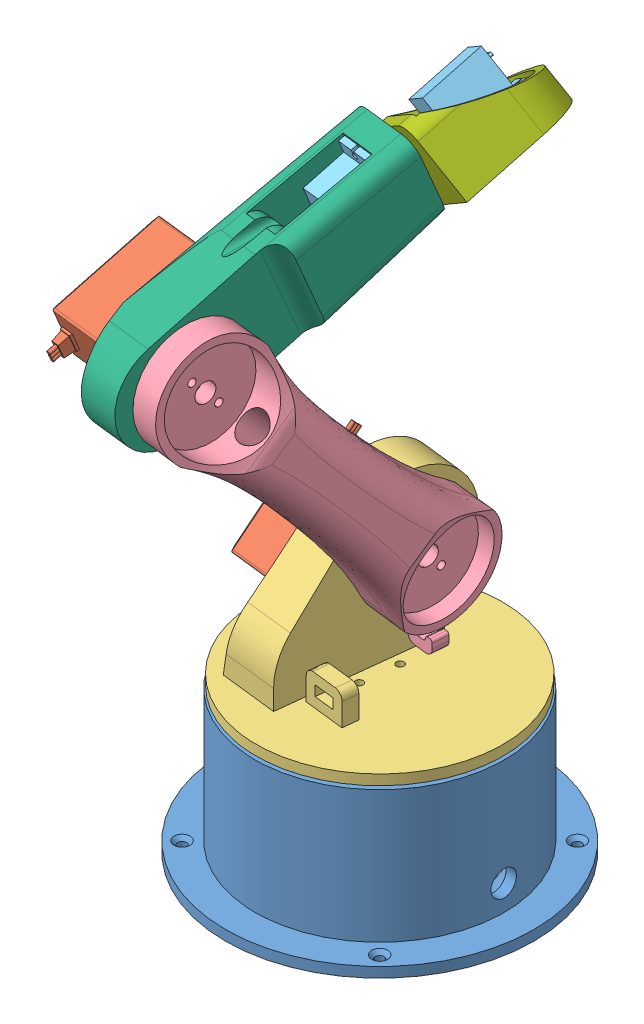
SolidWorks assembly Robotic Arm, configuration Default. Lengths in mm.
Overall size (121.25 257.34 174.58).
10 component instances, 7 part files, 24 mates.
Components (placement in the parent):
- Base-1: Base [Default] at (40.7793 36.1076 92.8796) size (121.25 56 121.25)
- Servo Motor MG996R-1: Servo Motor MG996R [Default] at (30.5293 45.3076 92.8796) x (-1 0 0) z (0 0 -1) size (55.8 47.4 21)
- Waist-1: Waist [Default] at (40.7793 93.1076 92.8796) x (0.993555 0 0.113355) z (-0.113355 0 0.993555) size (97 64.78 97)
- Servo Motor MG996R-2: Servo Motor MG996R [Default] at (-7.3675 126.313 80.8505) x (-0.080154 -0.707107 0.702549) z (-0.080154 0.707107 0.702549) size (55.8 47.4 21)
- Arm 01-1: Arm 01 [Default] at (40.5486 133.5608 79.0224) x (0.085272 0.658869 -0.747409) z (0.993555 0 0.113355) size (54.87 166.68 26.36)
- Servo Motor Micro  9g-1: Servo Motor Micro  9g [Default] at (27.4329 247.0974 99.587) x (-0.042658 0.926487 0.3739) z (-0.993555 0 -0.113355) size (32.6 29.9 12.4)
- Servo Motor MG996R-7: Servo Motor MG996R [Default] at (-14.4318 227.6891 142.7687) x (0.105022 0.376326 -0.920516) z (0.042658 -0.926487 -0.3739) size (55.8 47.4 21)
- Arm 02 v3-1: Arm 02 v3 [Default] at (30.0586 237.1407 125.0931) x (-0.042658 0.926487 0.3739) z (-0.993555 0 -0.113355) size (38.57 115 28.32)
- Arm 03-1: Arm 03 [Default] at (34.5638 256.4879 71.7578) x (0.75464 0.572691 0.320225) z (-0.64768 0.728289 0.223845) size (33 46 28)
- Servo Motor Micro  9g-2: Servo Motor Micro  9g [Default] at (27.5451 275.7024 53.9349) x (-0.105022 -0.376326 0.920516) z (0.75464 0.572691 0.320225) size (32.6 29.9 12.4)
Mates (geometry in assembly coordinates):
- Coincident1: coincident: plane of Base-1 through (40.7793 74.1076 105.8796) normal (0 1 0); plane of Servo Motor MG996R-1 through (57.8293 74.1076 102.1296) normal (0 -1 0)
- Concentric1: concentric: cylinder of Base-1 through (54.5293 66.9076 87.8796) axis (0 1 0) radius 1.3; cylinder of Servo Motor MG996R-1 through (54.5293 69.7076 87.8796) axis (0 1 0) radius 2.1
- Concentric4: concentric: cylinder of Base-1 through (6.5293 66.9076 97.8796) axis (0 1 0) radius 1.3; cylinder of Servo Motor MG996R-1 through (6.5293 69.7076 97.8796) axis (0 1 0) radius 2.1
- Concentric5: concentric: cylinder of Base-1 through (40.7793 92.1076 92.8796) axis (0 -1 0) radius 49; cylinder of Waist-1 through (40.7793 97.1076 92.8796) axis (0 -1 0) radius 48.5
- Distance1: distance = 1 mm: plane of Base-1 through (40.7793 92.1076 92.8796) normal (0 1 0); plane of Waist-1 through (40.7793 93.1076 92.8796) normal (0 -1 0)
- Coincident4: coincident: plane of Waist-1 through (22.8953 93.1076 90.8392) normal (-0.993555 0 -0.113355); plane of Servo Motor MG996R-2 through (26.561 139.0763 58.709) normal (0.993555 0 0.113355)
- Coincident5: coincident: plane of Waist-1 through (-9.1378 119.0651 102.5331) normal (0.080154 0.707107 -0.702549); plane of Servo Motor MG996R-2 through (26.9293 119.0651 106.648) normal (-0.080154 -0.707107 0.702549)
- Coincident6: coincident: plane of Waist-1 through (-9.1378 119.0651 102.5331) normal (0.080154 -0.707107 -0.702549); plane of Servo Motor MG996R-2 through (30.2156 148.0565 77.8435) normal (-0.080154 0.707107 0.702549)
- Coincident7: coincident: plane of Servo Motor MG996R-2 through (40.5486 133.5608 79.0224) normal (0.993555 0 0.113355); plane of Arm 01-1 through (40.5486 133.5608 79.0224) normal (-0.993555 0 -0.113355)
- Concentric8: concentric: cylinder of Servo Motor MG996R-2 through (40.5486 133.5608 79.0224) axis (-0.993555 0 -0.113355) radius 10.5; cylinder of Arm 01-1 through (45.5163 133.5608 79.5891) axis (-0.993555 0 -0.113355) radius 21
- Coincident25: coincident: plane of Servo Motor MG996R-7 through (19.0396 246.5328 124.6339) normal (0.993555 0 0.113355); plane of Arm 02 v3-1 through (19.1295 237.1407 123.8462) normal (-0.993555 0 -0.113355)
- Coincident26: coincident: plane of Servo Motor MG996R-7 through (20.614 210.478 162.0009) normal (0.042658 -0.926487 -0.3739); plane of Arm 02 v3-1 through (14.8514 210.478 161.3435) normal (-0.042658 0.926487 0.3739)
- Coincident27: coincident: plane of Servo Motor MG996R-7 through (24.9199 225.9073 124.2598) normal (0.105022 0.376326 -0.920516); plane of Arm 02 v3-1 through (19.1573 225.9073 123.6023) normal (-0.105022 -0.376326 0.920516)
- Concentric13: concentric: cylinder of Arm 01-1 through (31.5852 223.8318 157.5769) axis (0.993555 0 0.113355) radius 3.75; cylinder of Servo Motor MG996R-7 through (31.5862 223.8318 157.577) axis (-0.993555 0 -0.113355) radius 10.5
- Coincident28: coincident: plane of Arm 01-1 through (40.5486 133.5608 79.0224) normal (-0.993555 0 -0.113355); plane of Servo Motor MG996R-7 through (31.5862 223.8318 157.577) normal (0.993555 0 0.113355)
- Concentric14: concentric: cylinder of Servo Motor Micro  9g-1 through (30.7906 253.6245 70.1567) axis (-0.105022 -0.376326 0.920516) radius 2.5; cylinder of Arm 02 v3-1 through (30.3863 252.1756 73.7006) axis (0.105022 0.376326 -0.920516) radius 6.5
- Coincident30: coincident: plane of Servo Motor Micro  9g-1 through (22.4732 268.9919 88.3634) normal (0.105022 0.376326 -0.920516); plane of Arm 02 v3-1 through (23.6724 236.4721 75.2055) normal (-0.105022 -0.376326 0.920516)
- Parallel3: parallel: plane of Servo Motor Micro  9g-1 through (36.417 245.0202 75.5372) normal (0.993555 0 0.113355); plane of Arm 02 v3-1 through (36.5886 236.4721 76.6791) normal (-0.993555 0 -0.113355)
- Concentric15: concentric: cylinder of Servo Motor Micro  9g-1 through (30.7906 253.6245 70.1567) axis (-0.105022 -0.376326 0.920516) radius 2.5; cylinder of Arm 03-1 through (32.0584 258.1671 59.0451) axis (-0.105022 -0.376326 0.920516) radius 2.5
- Coincident31: coincident: plane of Servo Motor Micro  9g-1 through (30.7906 253.6245 70.1567) normal (0.105022 0.376326 -0.920516); plane of Arm 03-1 through (34.5638 256.4879 71.7578) normal (-0.105022 -0.376326 0.920516)
- Concentric16: concentric: cylinder of Arm 03-1 through (46.572 256.829 42.8495) axis (-0.64768 0.728289 0.223845) radius 6.5; cylinder of Servo Motor Micro  9g-2 through (47.4463 255.8458 42.5473) axis (-0.64768 0.728289 0.223845) radius 2.5
- Parallel6: parallel: plane of Arm 03-1 through (38.9624 247.9896 56.2923) normal (0.75464 0.572691 0.320225); plane of Servo Motor Micro  9g-2 through (38.4963 260.1634 36.556) normal (-0.75464 -0.572691 -0.320225)
- Parallel9: parallel: plane of Arm 03-1 through (41.3779 256.6451 35.1205) normal (-0.105022 -0.376326 0.920516); plane of Servo Motor Micro  9g-2 through (47.8539 267.2647 40.5267) normal (0.105022 0.376326 -0.920516)
- Coincident46: coincident: plane of Arm 03-1 through (24.3792 244.4895 65.6906) normal (-0.64768 0.728289 0.223845); plane of Servo Motor Micro  9g-2 through (45.6263 272.2416 36.8755) normal (0.64768 -0.728289 -0.223845)
